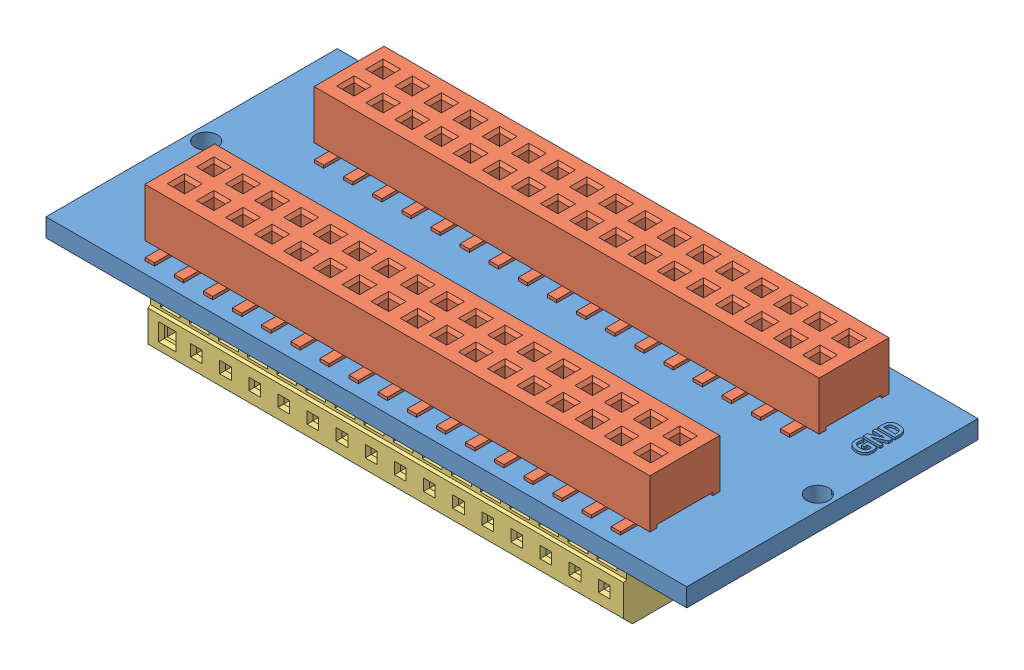
SolidWorks assembly EIB_millmax, configuration Default. Lengths in mm.
Overall size (27.94 8.65 12.7).
5 component instances, 3 part files, 12 mates.
Components (placement in the parent):
- EIB_millmax_PCB-1: EIB_millmax_PCB [Default] at origin size (27.94 0.9 12.7)
- Samtec-CLP-117-02-L-D-1: Samtec-CLP-117-02-L-D [LEAD STYLE2PINS17PLATINGLROWD] at (0.2159 0.927 3.691) size (22.02 4.09 4.6)
- Samtec-CLP-117-02-L-D-3: Samtec-CLP-117-02-L-D [LEAD STYLE2PINS17PLATINGLROWD] at (0.2159 0.927 -3.691) size (22.02 4.09 4.6)
- Samtec-CLP-116-02-L-DH-1: Samtec-CLP-116-02-L-DH [LEAD STYLE2PINS16PLATINGLROWDH] at (-0.4191 -1.7145 -2.04) x (1 0 0) z (0 1 0) size (20.75 4.57 4.32)
- Samtec-CLP-116-02-L-DH-2: Samtec-CLP-116-02-L-DH [LEAD STYLE2PINS16PLATINGLROWDH] at (-0.4191 -1.7145 2.04) x (-1 0 0) z (0 1 0) size (20.75 4.57 4.32)
Mates (geometry in assembly coordinates):
- Coincident1: coincident anti-aligned: plane of EIB_millmax_PCB-1 through (0 0.8 0) normal (0 1 0); plane of Samtec-CLP-117-02-L-D-1 through (-9.7409 0.8 4.834) normal (0 -1 0)
- Distance1: distance = 0.5 mm aligned: plane of Samtec-CLP-117-02-L-D-1 through (-9.7409 0.927 5.85) normal (0 0 1); plane of EIB_millmax_PCB-1 through (-13.97 0.8 6.35) normal (0 0 1)
- Distance2: distance = 3.175 mm aligned: plane of Samtec-CLP-117-02-L-D-1 through (-10.795 3.0479 2.167) normal (-1 0 0); plane of EIB_millmax_PCB-1 through (-13.97 0.8 -6.35) normal (-1 0 0)
- Coincident3: coincident anti-aligned: plane of EIB_millmax_PCB-1 through (0 0.8 0) normal (0 1 0); plane of Samtec-CLP-117-02-L-D-3 through (-9.7409 0.8 -2.548) normal (0 -1 0)
- Distance5: distance = 0.5 mm aligned: plane of Samtec-CLP-117-02-L-D-3 through (-9.7409 0.927 -5.85) normal (0 0 -1); plane of EIB_millmax_PCB-1 through (-13.97 0.8 -6.35) normal (0 0 -1)
- Distance6: distance = 3.175 mm aligned: plane of Samtec-CLP-117-02-L-D-3 through (-10.795 3.0479 -5.215) normal (-1 0 0); plane of EIB_millmax_PCB-1 through (-13.97 0.8 -6.35) normal (-1 0 0)
- Coincident4: coincident anti-aligned: plane of EIB_millmax_PCB-1 through (0 0 0) normal (0 -1 0); plane of Samtec-CLP-116-02-L-DH-1 through (-9.7409 0 -5.85) normal (0 1 0)
- Coincident5: coincident aligned: plane of Samtec-CLP-117-02-L-D-3 through (-10.795 3.0479 -5.215) normal (-1 0 0); plane of Samtec-CLP-116-02-L-DH-1 through (-10.795 -3.429 -5.088) normal (-1 0 0)
- Coincident6: coincident aligned: plane of Samtec-CLP-117-02-L-D-3 through (-9.7409 0.927 -5.85) normal (0 0 -1); plane of Samtec-CLP-116-02-L-DH-1 through (-9.7409 0 -5.85) normal (0 0 -1)
- Coincident7: coincident anti-aligned: plane of EIB_millmax_PCB-1 through (0 0 0) normal (0 -1 0); plane of Samtec-CLP-116-02-L-DH-2 through (8.9027 0 5.85) normal (0 1 0)
- Coincident8: coincident aligned: plane of Samtec-CLP-117-02-L-D-1 through (-10.795 3.0479 2.167) normal (-1 0 0); plane of Samtec-CLP-116-02-L-DH-2 through (-10.795 -3.429 5.088) normal (-1 0 0)
- Coincident9: coincident aligned: plane of Samtec-CLP-117-02-L-D-1 through (-9.7409 0.927 5.85) normal (0 0 1); plane of Samtec-CLP-116-02-L-DH-2 through (-10.1473 0 5.85) normal (0 0 1)
